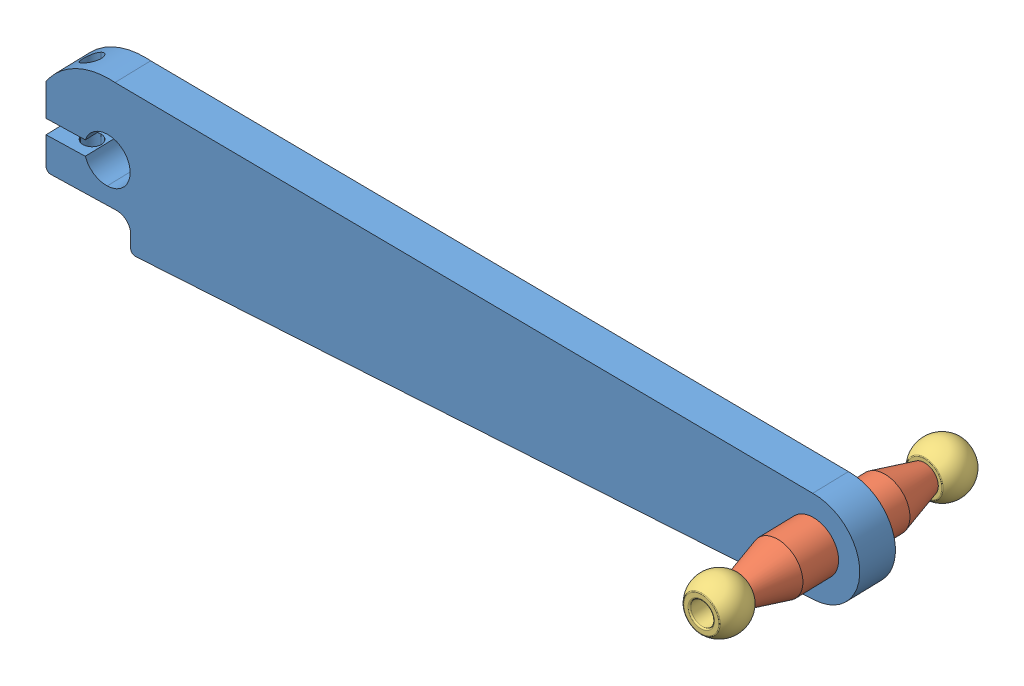
SolidWorks assembly CanhTayTren_Simscape, configuration Default. Lengths in mm.
Overall size (173.15 30.85 58.28).
5 component instances, 3 part files, 8 mates.
Components (placement in the parent):
- CanhTayTren_Simscape_2-1: CanhTayTren_Simscape_2 [Default] at origin size (173.15 30.85 12.61)
- Long Tru Nhua-1: Long Tru Nhua [Default] at (150.0533 0 0) x (0.999645 0 -0.026657) z (0 -1 0) size (11 17 11)
- Long Tru Nhua-2: Long Tru Nhua [Default] at (149.8401 0 -7.9972) x (0.999645 0 -0.026657) z (0 1 0) size (11 17 11)
- Ball Joint M5-1: Ball Joint M5 [Default] at (150.6131 0 20.9906) x (0.999645 0 -0.026657) z (0 -1 0) size (11.1 8 11.1)
- Ball Joint M5-2: Ball Joint M5 [Default] at (149.2803 0 -28.9878) x (0.99625 -0.082345 -0.026567) z (-0.082316 -0.996604 0.002195) size (11.1 8 11.1)
Mates (geometry in assembly coordinates):
- Coincident6: coincident aligned: line of Long Tru Nhua-2 through (149.2183 0 -31.3118) axis (-0.026657 0 -0.999645); line of Ball Joint M5-2 through (148.9704 0 -40.6085) axis (-0.026657 0 -0.999645)
- Coincident7: coincident anti-aligned: plane of Long Tru Nhua-2 through (151.9774 0 -40.3885) normal (-0.026657 0 -0.999645); plane of Ball Joint M5-2 through (151.4691 -0.2059 -40.375) normal (0.026657 0 0.999645)
- Coincident8: coincident anti-aligned: line of Long Tru Nhua-1 through (150.4459 0 14.7208) axis (0.026657 0 0.999645); line of Ball Joint M5-1 through (150.891 0 31.411) axis (-0.026657 0 -0.999645)
- Coincident9: coincident anti-aligned: plane of Long Tru Nhua-1 through (153.6847 0 23.6376) normal (0.026657 0 0.999645); plane of Ball Joint M5-1 through (153.1849 0 23.6509) normal (-0.026657 0 -0.999645)
- Coincident10: coincident aligned: line of CanhTayTren_Simscape_2-1 through (149.8401 0 -7.9972) axis (0.026657 0 0.999645); line of Long Tru Nhua-2 through (149.6268 0 -15.9943) axis (0.026657 0 0.999645)
- Coincident11: coincident anti-aligned: plane of CanhTayTren_Simscape_2-1 through (73.3673 0 -5.9579) normal (-0.026657 0 -0.999645); plane of Long Tru Nhua-2 through (154.8383 0 -8.1304) normal (0.026657 0 0.999645)
- Coincident12: coincident anti-aligned: line of CanhTayTren_Simscape_2-1 through (149.8401 0 -7.9972) axis (0.026657 0 0.999645); line of Long Tru Nhua-1 through (150.2666 0 7.9972) axis (-0.026657 0 -0.999645)
- Coincident13: coincident anti-aligned: plane of CanhTayTren_Simscape_2-1 through (73.5805 0 2.0393) normal (0.026657 0 0.999645); plane of Long Tru Nhua-1 through (155.0515 0 -0.1333) normal (-0.026657 0 -0.999645)
